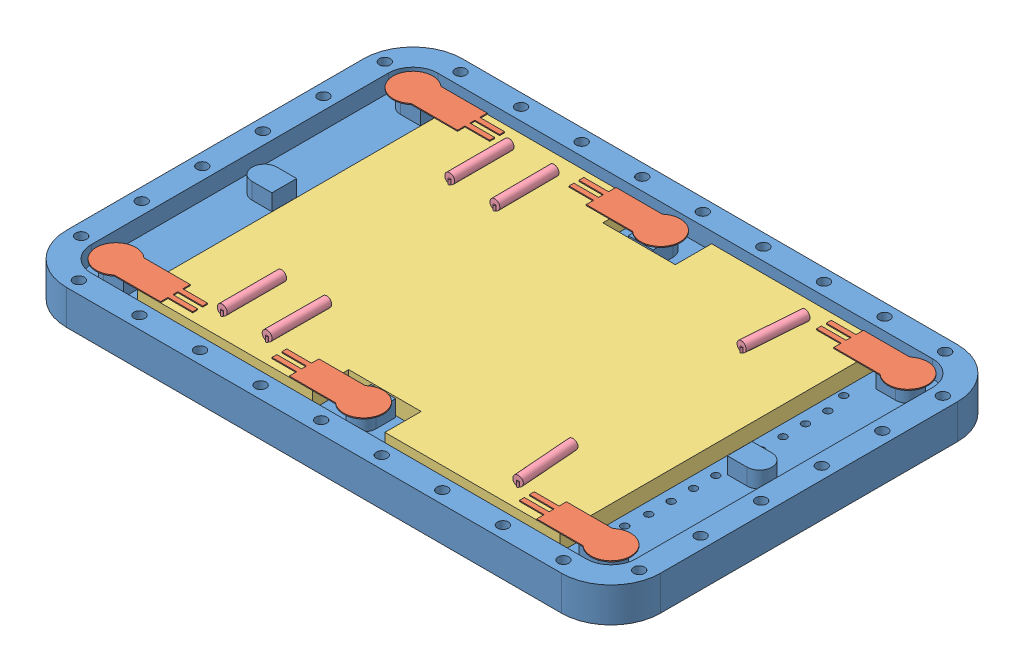
SolidWorks assembly circuit, configuration Default. Lengths in mm.
Overall size (120 8.8 80).
14 component instances, 4 part files, 28 mates.
Components (placement in the parent):
- foot_revised_1-1: foot_revised_1 [Default] at (47.3337 55.0351 93.5464) size (120 7 80)
- fsr-1: fsr [Default] at (-2.6663 61.9351 63.5464) size (21 0.2 8)
- fsr-2: fsr [Default] at (97.3337 61.9351 63.5464) x (-1 0 0) z (0 0 -1) size (21 0.2 8)
- fsr-3: fsr [Default] at (-2.6663 61.9351 123.5464) size (21 0.2 8)
- fsr-4: fsr [Default] at (47.3337 61.9351 63.5464) x (-1 0 0) z (0 0 -1) size (21 0.2 8)
- fsr-5: fsr [Default] at (47.3337 61.9351 123.5464) x (-1 0 0) z (0 0 -1) size (21 0.2 8)
- fsr-6: fsr [Default] at (97.3337 61.9351 123.5464) x (-1 0 0) z (0 0 -1) size (21 0.2 8)
- Part2^circuit-1: Part2^circuit [Default] at (47.3337 58.5351 93.5464) x (1 0 0) z (0 1 0) size (92.41 66.11 3.3) (virtual)
- resistor-1: resistor [Default] at (17.7697 62.8351 116.5242) x (-1 0 0) z (0 0 1) size (2 5 12.5)
- resistor-7: resistor [Default] at (26.8664 62.8351 116.5242) x (-0.999986 0 -0.005211) z (-0.005211 0 0.999986) size (2 5 12.5)
- resistor-8: resistor [Default] at (77.1205 62.8351 116.5904) x (-0.997077 0 0.076405) z (0.076405 0 0.997077) size (2 5 12.5)
- resistor-9: resistor [Default] at (17.7697 62.8351 70.5686) x (-1 0 0) z (0 0 1) size (2 5 12.5)
- resistor-10: resistor [Default] at (26.8664 62.8351 70.5687) x (-0.999986 0 0.005211) z (0.005211 0 0.999986) size (2 5 12.5)
- resistor-11: resistor [Default] at (77.1205 62.8351 70.5024) x (-0.997077 0 -0.076405) z (-0.076405 0 0.997077) size (2 5 12.5)
Mates (geometry in assembly coordinates):
- Coincident1: coincident anti-aligned: plane of fsr-3 through (-2.6663 61.8351 123.5464) normal (0 -1 0); plane of foot_revised_1-1 through (47.3337 61.8351 93.5464) normal (0 1 0)
- Concentric1: concentric aligned: cylinder of foot_revised_1-1 through (-2.6663 61.8351 123.5464) axis (0 -1 0) radius 2.5; cylinder of fsr-3 through (-2.6663 62.0351 123.5464) axis (0 -1 0) radius 4
- Coincident2: coincident anti-aligned: plane of foot_revised_1-1 through (47.3337 61.8351 93.5464) normal (0 1 0); plane of fsr-5 through (47.3337 61.8351 123.5464) normal (0 -1 0)
- Concentric2: concentric aligned: cylinder of foot_revised_1-1 through (47.3337 61.8351 123.5464) axis (0 -1 0) radius 2.5; cylinder of fsr-5 through (47.3337 62.0351 123.5464) axis (0 -1 0) radius 4
- Concentric3: concentric aligned: cylinder of foot_revised_1-1 through (-2.6663 61.8351 63.5464) axis (0 -1 0) radius 2.5; cylinder of fsr-1 through (-2.6663 62.0351 63.5464) axis (0 -1 0) radius 4
- Coincident3: coincident anti-aligned: plane of foot_revised_1-1 through (47.3337 61.8351 93.5464) normal (0 1 0); plane of fsr-1 through (-2.6663 61.8351 63.5464) normal (0 -1 0)
- Concentric4: concentric aligned: cylinder of foot_revised_1-1 through (47.3337 61.8351 63.5464) axis (0 -1 0) radius 2.5; cylinder of fsr-4 through (47.3337 62.0351 63.5464) axis (0 -1 0) radius 4
- Coincident4: coincident anti-aligned: plane of foot_revised_1-1 through (47.3337 61.8351 93.5464) normal (0 1 0); plane of fsr-4 through (47.3337 61.8351 63.5464) normal (0 -1 0)
- Concentric5: concentric aligned: cylinder of foot_revised_1-1 through (97.3337 61.8351 63.5464) axis (0 -1 0) radius 2.5; cylinder of fsr-2 through (97.3337 62.0351 63.5464) axis (0 -1 0) radius 4
- Coincident5: coincident anti-aligned: plane of foot_revised_1-1 through (47.3337 61.8351 93.5464) normal (0 1 0); plane of fsr-2 through (97.3337 61.8351 63.5464) normal (0 -1 0)
- Coincident6: coincident anti-aligned: plane of foot_revised_1-1 through (47.3337 61.8351 93.5464) normal (0 1 0); plane of fsr-6 through (97.3337 61.8351 123.5464) normal (0 -1 0)
- Concentric6: concentric aligned: cylinder of foot_revised_1-1 through (97.3337 61.8351 123.5464) axis (0 -1 0) radius 2.5; cylinder of fsr-6 through (97.3337 62.0351 123.5464) axis (0 -1 0) radius 4
- Parallel1: parallel anti-aligned: plane of foot_revised_1-1 through (-7.6663 58.5351 128.5464) normal (0 0 -1); plane of fsr-3 through (-2.6663 62.0351 126.5464) normal (0 0 1)
- Parallel2: parallel anti-aligned: plane of foot_revised_1-1 through (-7.6663 58.5351 128.5464) normal (0 0 -1); plane of fsr-5 through (47.3337 62.0351 126.5464) normal (0 0 1)
- Parallel3: parallel anti-aligned: plane of foot_revised_1-1 through (-7.6663 58.5351 128.5464) normal (0 0 -1); plane of fsr-6 through (97.3337 62.0351 126.5464) normal (0 0 1)
- Parallel4: parallel anti-aligned: plane of foot_revised_1-1 through (102.3337 58.5351 58.5464) normal (0 0 1); plane of fsr-2 through (97.3337 62.0351 60.5464) normal (0 0 -1)
- Parallel5: parallel anti-aligned: plane of foot_revised_1-1 through (102.3337 58.5351 58.5464) normal (0 0 1); plane of fsr-4 through (47.3337 62.0351 60.5464) normal (0 0 -1)
- Parallel6: parallel aligned: plane of foot_revised_1-1 through (102.3337 58.5351 58.5464) normal (0 0 1); plane of fsr-1 through (-2.6663 62.0351 66.5464) normal (0 0 1)
- InPlace1: in place: plane of foot_revised_1-1 through (47.3337 58.5351 93.5464) normal (0 1 0); plane of ? through (0 58.5351 0) normal (0 1 0); moOrthogonalPlaneRef_w of foot_revised_1-1 through (47.3337 58.5351 93.5464) normal (0 1 0); plane of ? through (0 58.5351 0) normal (0 0 -1); plane of foot_revised_1-1 through (47.3337 58.5351 93.5464) normal (0 1 0); plane of ? through (0 58.5351 0) normal (1 0 0); plane of foot_revised_1-1 through (47.3337 58.5351 93.5464) normal (0 1 0); unknown of Part2^circuit-1
- Coincident13: coincident aligned: plane of foot_revised_1-1; plane of Part2^circuit-1
- Coincident14: coincident aligned: moOrthogonalPlaneRef_w of foot_revised_1-1 through (47.3337 58.5351 93.5464) normal (0 0 -1); plane of Part2^circuit-1 through (47.3337 58.5351 93.5464) normal (0 0 -1)
- Coincident15: coincident anti-aligned: moOrthogonalPlaneRef_w of foot_revised_1-1 through (47.3337 58.5351 93.5464) normal (-1 0 0); plane of Part2^circuit-1 through (47.3337 58.5351 93.5464) normal (1 0 0)
- Distance1: distance = 3 mm anti-aligned: plane of Part2^circuit-1 through (-2.6663 61.8351 123.5464) normal (0 1 0); plane of resistor-1 through (17.7697 58.8351 122.5242) normal (0 -1 0)
- Parallel10: parallel aligned: plane of foot_revised_1-1 through (102.3337 58.5351 128.5464) normal (-1 0 0); plane of resistor-1 through (17.7697 62.8351 116.5242) normal (-1 0 0)
- Distance2: distance = 3 mm anti-aligned: plane of resistor-7 through (26.8351 58.8351 122.5241) normal (0 -1 0); plane of Part2^circuit-1 through (-2.6663 61.8351 123.5464) normal (0 1 0)
- Concentric7: concentric anti-aligned: circle of Part2^circuit-1; cylinder of resistor-7 through (26.8976 58.8351 110.5242) axis (0 1 0) radius 0.25
- Distance3: distance = 3 mm anti-aligned: plane of resistor-8 through (77.5789 58.8351 122.5729) normal (0 -1 0); plane of Part2^circuit-1 through (-2.6663 61.8351 123.5464) normal (0 1 0)
- Coincident10: coincident: point of Part2^circuit-1; cylinder of resistor-8 through (76.6621 58.8351 110.608) axis (0 1 0) radius 0.25
